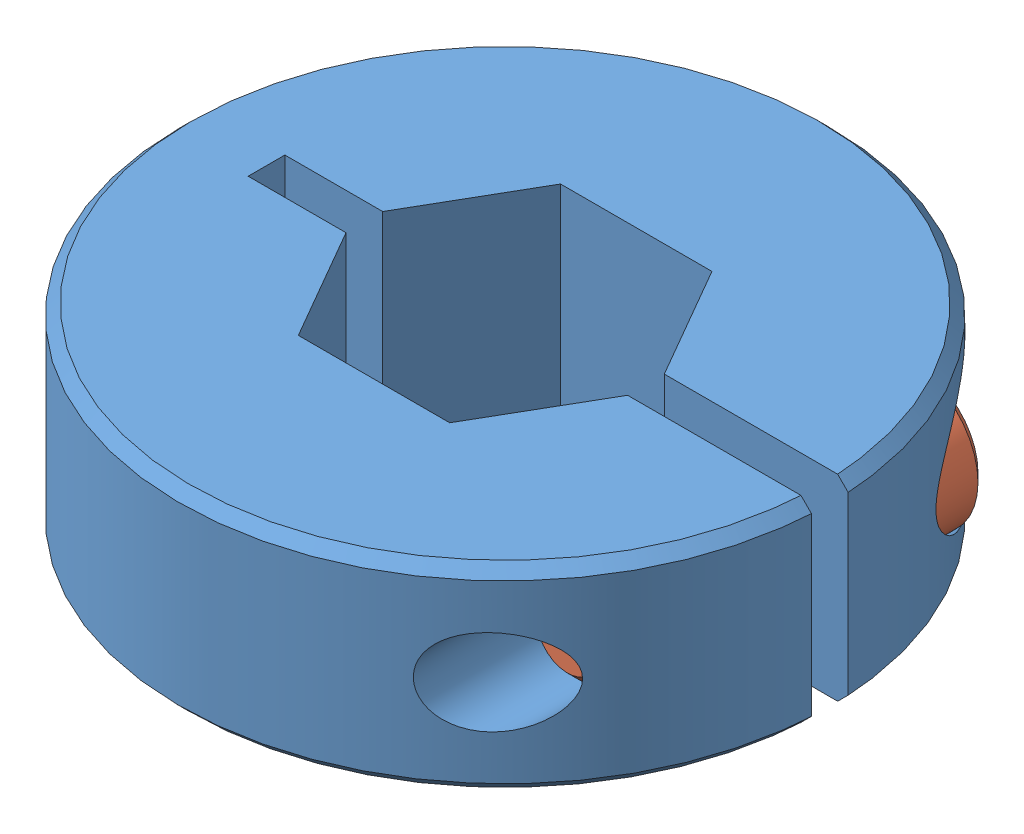
SolidWorks assembly am-1238+Collar+Clamp,+0.5''+Hex+Bore,+Aluminum, configuration Default. Lengths in mm.
Overall size (31.47 9.53 31.5).
2 component instances, 2 part files, 0 mates.
Components (placement in the parent):
- am-1238 Clamp Only-1: am-1238 Clamp Only [Default] at origin size (31.47 9.53 31.5)
- am-1238 Screw Only_91251A194-1: am-1238 Screw Only_91251A194 [Default] at (10.7699 4.7625 7.747) size (6.86 6.86 17.11)
